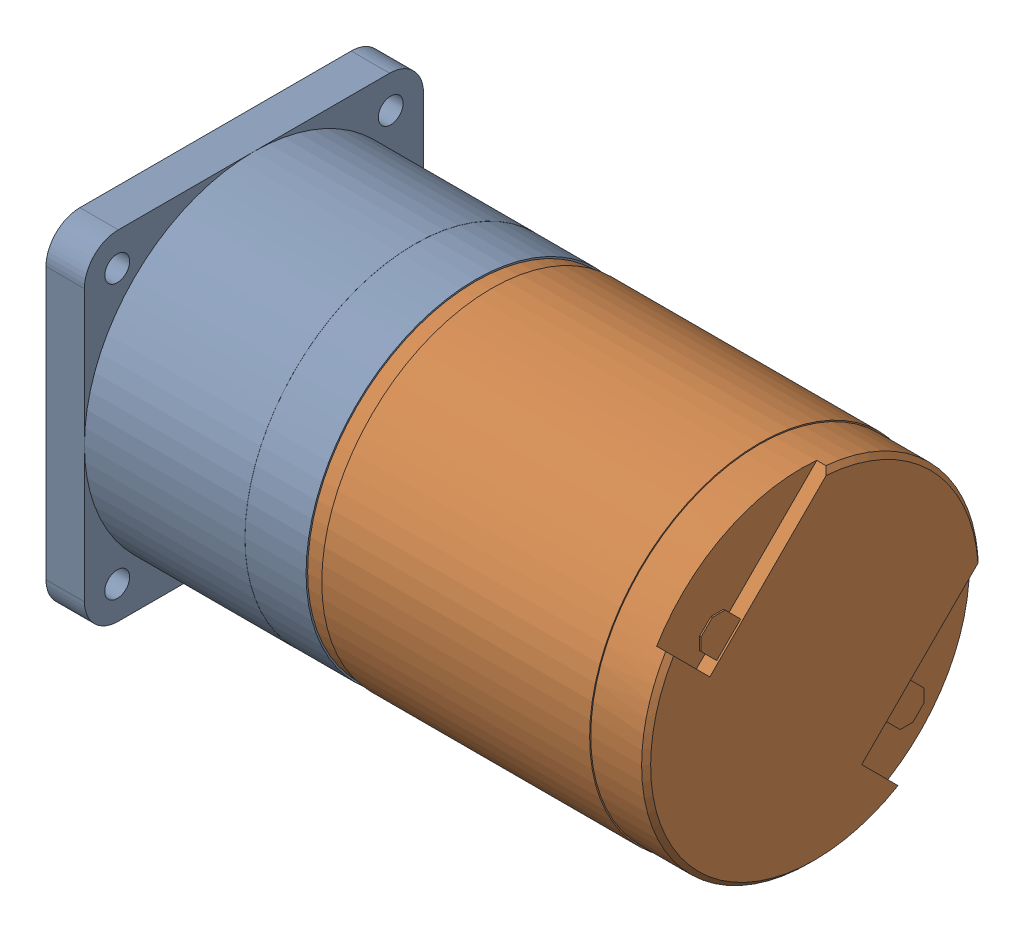
SolidWorks assembly Moto-réducteur, configuration Défaut. Lengths in mm.
Overall size (58.95 30 30).
2 component instances, 2 part files, 3 mates.
Components (placement in the parent):
- Réducteur GS30-1: Réducteur GS30 [Défaut] at (5.0508 1.4306 0) size (28.95 30 30)
- Moteur F2130-1: Moteur F2130 [Défaut] at (35.0508 1.4306 0) size (40.2 30 30)
Mates (geometry in assembly coordinates):
- Coïncidente1: coincident anti-aligned: plane of Réducteur GS30-1 through (5.0508 1.4306 0) normal (1 0 0); plane of Moteur F2130-1 through (5.0508 16.2806 0) normal (-1 0 0)
- Coaxiale1: concentric aligned: circle of Réducteur GS30-1; circle of Moteur F2130-1
- Angle1: planar angle = 3.926991 rad anti-aligned: plane of Réducteur GS30-1 through (-17.9492 16.4306 15) normal (0 0 1); plane of Moteur F2130-1 through (33.8508 24.6088 -9.7432) normal (0 0.707107 0.707107)
